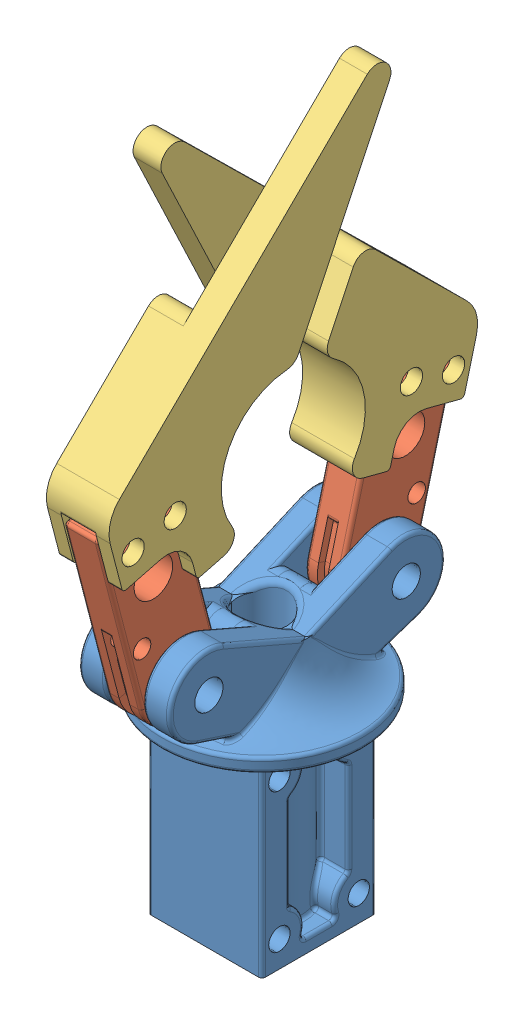
SolidWorks assembly MS-SA-0013f-03-Center Claw, configuration Default. Lengths in mm.
Overall size (36.64 129.77 85.39).
5 component instances, 3 part files, 12 mates.
Components (placement in the parent):
- MS-P-0064-03 Gripper Center Claw Piece-1: MS-P-0064-03 Gripper Center Claw Piece [Default] at (6.1332 40.3612 86.7065) size (36.64 54.77 50.29)
- MS-P-0067-03 Gripper Claw Base-1: MS-P-0067-03 Gripper Claw Base [Default] at (6.3237 40.3612 68.7042) x (0 -0.251804 -0.967778) z (1 0 0) size (14.29 38.89 6.35)
- MS-P-0067-03 Gripper Claw Base-2: MS-P-0067-03 Gripper Claw Base [Default] at (5.9427 40.3612 104.7087) x (0 -0.251804 0.967778) z (-1 0 0) size (14.29 38.89 6.35)
- MS-P-0065-03 Gripper Claw v5-2: MS-P-0065-03 Gripper Claw v5 [Default] at (9.4987 57.5235 71.6204) x (1 0 0) z (0 0.251804 0.967778) size (11.43 54.73 61.98)
- MS-P-0065-03 Gripper Claw v5-4: MS-P-0065-03 Gripper Claw v5 [Default] at (2.7677 57.5235 101.7926) x (-1 0 0) z (0 0.251804 -0.967778) size (11.43 54.73 61.98)
Mates (geometry in assembly coordinates):
- Concentric1: concentric anti-aligned: circle of MS-P-0064-03 Gripper Center Claw Piece-1; circle of MS-P-0066-03 Gripper Claw Base-1
- Coincident1: coincident anti-aligned: plane of MS-P-0064-03 Gripper Center Claw Piece-1 through (9.4987 40.3612 86.7065) normal (-1 0 0); plane of MS-P-0067-03 Gripper Claw Base-1 through (9.4987 40.3612 68.7042) normal (1 0 0)
- Concentric3: concentric anti-aligned: circle of MS-P-0067-03 Gripper Claw Base-1; circle of MS-P-0065-03 Gripper Claw v3-8
- Concentric4: concentric aligned: circle of MS-P-0067-03 Gripper Claw Base-1; circle of MS-P-0065-03 Gripper Claw v3-8
- Coincident27: coincident anti-aligned: plane of MS-P-0067-03 Gripper Claw Base-1 through (9.4987 40.3612 68.7042) normal (1 0 0); plane of MS-P-0065-03 Gripper Claw v3-8 through (9.4987 69.4073 53.7652) normal (-1 0 0)
- Concentric6: concentric aligned: circle of MS-P-0067-03 Gripper Claw Base-1; circle of MS-P-0065-03 Gripper Claw v4-1
- Concentric7: concentric aligned: circle of MS-P-0067-03 Gripper Claw Base-1; circle of MS-P-0065-03 Gripper Claw v4-1
- Coincident32: coincident anti-aligned: plane of MS-P-0067-03 Gripper Claw Base-1 through (3.1487 40.3612 68.7042) normal (-1 0 0); plane of MS-P-0065-03 Gripper Claw v4-1 through (3.1487 16.5477 90.3048) normal (1 0 0)
- Parallel1: parallel aligned: plane of MS-P-0064-03 Gripper Center Claw Piece-1 through (16.5472 -7.2638 86.7065) normal (1 0 0); plane of MS-P-0066-03 PVC Pipe-1 through (-5455.3181 57.3295 94.139) normal (1 0 0)
- Concentric13: concentric aligned: circle of MS-P-0067-03 Gripper Claw Base-1; circle of MS-P-0065-03 Gripper Claw v5-2
- Coincident39: coincident anti-aligned: plane of MS-P-0067-03 Gripper Claw Base-1 through (9.4987 40.3612 68.7042) normal (1 0 0); plane of MS-P-0065-03 Gripper Claw v5-2 through (9.4987 57.5235 71.6204) normal (-1 0 0)
- Coincident40: coincident aligned: plane of MS-P-0067-03 Gripper Claw Base-1 through (9.4987 38.5623 61.7907) normal (0 -0.251804 -0.967778); plane of MS-P-0065-03 Gripper Claw v5-2 through (12.0387 53.9258 57.7933) normal (0 -0.251804 -0.967778)
